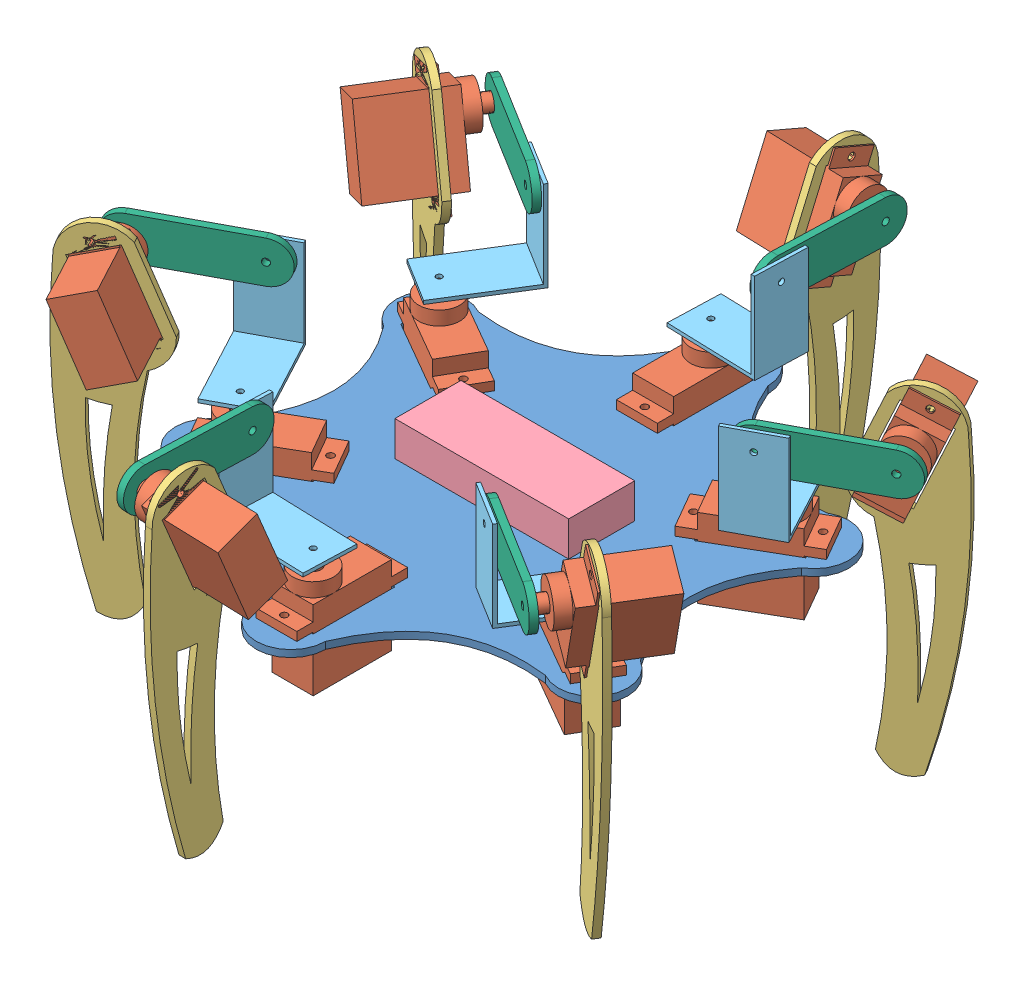
SolidWorks assembly Assem2, configuration Default. Lengths in mm.
Overall size (221.19 102.26 246.14).
33 component instances, 7 part files, 14 mates.
Components (placement in the parent):
- MainChasis-1: MainChasis [Default] at origin size (130.18 2 147.22)
- SG90-1: SG90 [Default] at (-57.6067 -13.9 26.4465) x (0.866025 0 -0.5) z (0.5 0 0.866025) size (31.9 29.9 11.8)
- FeetExternal-1: FeetExternal [Default] at (-76.0961 32.0511 38.2671) x (-0.815719 -0.379907 0.436203) z (-0.471559 0 -0.881835) size (43.01 92.88 2)
- SG90-2: SG90 [Default] at (-77.18 40.2162 56.8773) x (0.335016 -0.925024 -0.179149) z (0.815719 0.379907 -0.436203) size (31.9 29.9 11.8)
- BluePill-1: BluePill [Default] at (-0.5414 12 -1.3536) x (1 0 0) z (0 -1 0) size (50 19 10)
- 90degreejoint-1: 90degreejoint [Default] at (-53.0839 17 21.9923) x (0.471559 0 0.881835) z (0 -1 0) size (26 15 26)
- FeetInternal-2: FeetInternal [Default] at (-71.2628 37 19.8064) x (-0.881835 0 0.471559) z (-0.471559 0 -0.881835) size (42.02 12.02 2)
- SG90-8: SG90 [Default] at (-5.9 -13.9 63.1122) x (0 0 -1) z (1 0 0) size (31.9 29.9 11.8)
- SG90-9: SG90 [Default] at (51.7067 -13.9 36.6656) x (-0.866025 0 -0.5) z (0.5 0 -0.866025) size (31.9 29.9 11.8)
- SG90-10: SG90 [Default] at (57.6067 -13.9 -26.4465) x (-0.866025 0 0.5) z (-0.5 0 -0.866025) size (31.9 29.9 11.8)
- SG90-11: SG90 [Default] at (5.9 -13.9 -63.1122) x (0 0 1) z (-1 0 0) size (31.9 29.9 11.8)
- SG90-12: SG90 [Default] at (-51.7067 -13.9 -36.6656) x (0.866025 0 0.5) z (-0.5 0 0.866025) size (31.9 29.9 11.8)
- FeetExternal-2: FeetExternal [Default] at (-4.9078 32.0511 85.0347) x (-0.030096 -0.379907 0.924535) z (-0.999471 0 -0.032535) size (43.01 92.88 2)
- FeetExternal-3: FeetExternal [Default] at (71.1883 32.0511 46.7676) x (0.785623 -0.379907 0.488331) z (-0.527912 0 0.849299) size (43.01 92.88 2)
- FeetExternal-4: FeetExternal [Default] at (76.0961 32.0511 -38.2671) x (0.815719 -0.379907 -0.436203) z (0.471559 0 0.881835) size (43.01 92.88 2)
- FeetExternal-5: FeetExternal [Default] at (4.9078 32.0511 -85.0347) x (0.030096 -0.379907 -0.924535) z (0.999471 0 0.032535) size (43.01 92.88 2)
- FeetExternal-6: FeetExternal [Default] at (-71.1883 32.0511 -46.7676) x (-0.785623 -0.379907 -0.488331) z (0.527912 0 -0.849299) size (43.01 92.88 2)
- SG90-13: SG90 [Default] at (10.6671 40.2162 95.2785) x (0.01236 -0.925024 -0.379706) z (0.030096 0.379907 -0.924535) size (31.9 29.9 11.8)
- SG90-14: SG90 [Default] at (87.8471 40.2162 38.4012) x (-0.322655 -0.925024 -0.200558) z (-0.785623 0.379907 -0.488331) size (31.9 29.9 11.8)
- SG90-15: SG90 [Default] at (77.18 40.2162 -56.8773) x (-0.335016 -0.925024 0.179149) z (-0.815719 0.379907 0.436203) size (31.9 29.9 11.8)
- SG90-16: SG90 [Default] at (-10.6671 40.2162 -95.2785) x (-0.01236 -0.925024 0.379706) z (-0.030096 0.379907 0.924535) size (31.9 29.9 11.8)
- SG90-17: SG90 [Default] at (-87.8471 40.2162 -38.4012) x (0.322655 -0.925024 0.200558) z (0.785623 0.379907 0.488331) size (31.9 29.9 11.8)
- 90degreejoint-2: 90degreejoint [Default] at (-7.496 17 56.9681) x (0.999471 0 0.032535) z (0 -1 0) size (26 15 26)
- 90degreejoint-3: 90degreejoint [Default] at (45.5878 17 34.9758) x (0.527912 0 -0.849299) z (0 -1 0) size (26 15 26)
- 90degreejoint-4: 90degreejoint [Default] at (53.0839 17 -21.9923) x (-0.471559 0 -0.881835) z (0 -1 0) size (26 15 26)
- 90degreejoint-5: 90degreejoint [Default] at (7.496 17 -56.9681) x (-0.999471 0 -0.032535) z (0 -1 0) size (26 15 26)
- 90degreejoint-6: 90degreejoint [Default] at (-45.5878 17 -34.9758) x (-0.527912 0 0.849299) z (0 -1 0) size (26 15 26)
- FeetInternal-3: FeetInternal [Default] at (-18.4785 37 71.6186) x (-0.032535 0 0.999471) z (-0.999471 0 -0.032535) size (42.02 12.02 2)
- FeetInternal-4: FeetInternal [Default] at (52.7843 37 51.8121) x (0.849299 0 0.527912) z (-0.527912 0 0.849299) size (42.02 12.02 2)
- FeetInternal-5: FeetInternal [Default] at (71.2628 37 -19.8064) x (0.881835 0 -0.471559) z (0.471559 0 0.881835) size (42.02 12.02 2)
- FeetInternal-6: FeetInternal [Default] at (18.4785 37 -71.6186) x (0.032535 0 -0.999471) z (0.999471 0 0.032535) size (42.02 12.02 2)
- FeetInternal-7: FeetInternal [Default] at (-52.7843 37 -51.8121) x (-0.849299 0 -0.527912) z (0.527912 0 -0.849299) size (42.02 12.02 2)
- AA battery holder-1: AA battery holder [Default] at (0.4541 0 0.5631) x (1 0 0) z (0 -1 0) size (58 32 14)
Mates (geometry in assembly coordinates):
- Coincident10: coincident: circle of assembly; circle of assembly; circle of MainChasis-1; circle of SG90-1
- Concentric3: concentric: circle of assembly; circle of assembly; circle of MainChasis-1; circle of SG90-1
- Coincident13: coincident: circle of assembly; circle of assembly; circle of FeetExternal-1; circle of SG90-2
- Coincident14: coincident: circle of assembly; circle of assembly; circle of FeetExternal-1; circle of SG90-2
- Coincident21: coincident: plane of assembly; plane of assembly; plane of MainChasis-1 through (0 2 0) normal (0 1 0); plane of BluePill-1 through (-0.5414 2 -1.3536) normal (0 -1 0)
- Concentric7: concentric: circle of assembly; circle of assembly; circle of SG90-2; circle of FeetInternal-2
- Coincident24: coincident: plane of SG90-2 through (-91.2796 40.2162 30.5104) normal (-0.471559 0 -0.881835); plane of FeetInternal-2 through (-58.0352 37 12.7331) normal (0.471559 0 0.881835)
- Coincident25: coincident: plane of assembly; plane of assembly; plane of SG90-1 through (-57.6067 16 26.4465) normal (0 1 0); plane of 90degreejoint-1 through (-53.0839 16 21.9923) normal (0 -1 0)
- Concentric8: concentric: circle of assembly; circle of assembly; circle of SG90-9; circle of 90degreejoint-3
- Perpendicular1: perpendicular: plane of 90degreejoint-1 through (-59.4499 17 10.0876) normal (-0.471559 0 -0.881835); plane of FeetInternal-2 through (-58.9784 43.0098 10.9694) normal (0 1 0)
- Coincident35: coincident: plane of 90degreejoint-1 through (-58.9784 17 10.9694) normal (0.471559 0 0.881835); plane of FeetInternal-2 through (-58.9784 37 10.9694) normal (-0.471559 0 -0.881835)
- Concentric14: concentric: circle of 90degreejoint-1; circle of FeetInternal-2
- Parallel2: parallel: plane of 90degreejoint-1 through (-66.0637 42 13.6242) normal (0 1 0); plane of FeetInternal-2 through (-58.9784 43.0098 10.9694) normal (0 1 0)
- Coincident37: coincident: plane of assembly; plane of assembly; plane of MainChasis-1 through (0 0 0) normal (0 -1 0); plane of AA battery holder-1 through (0.4541 0 0.5631) normal (0 1 0)
